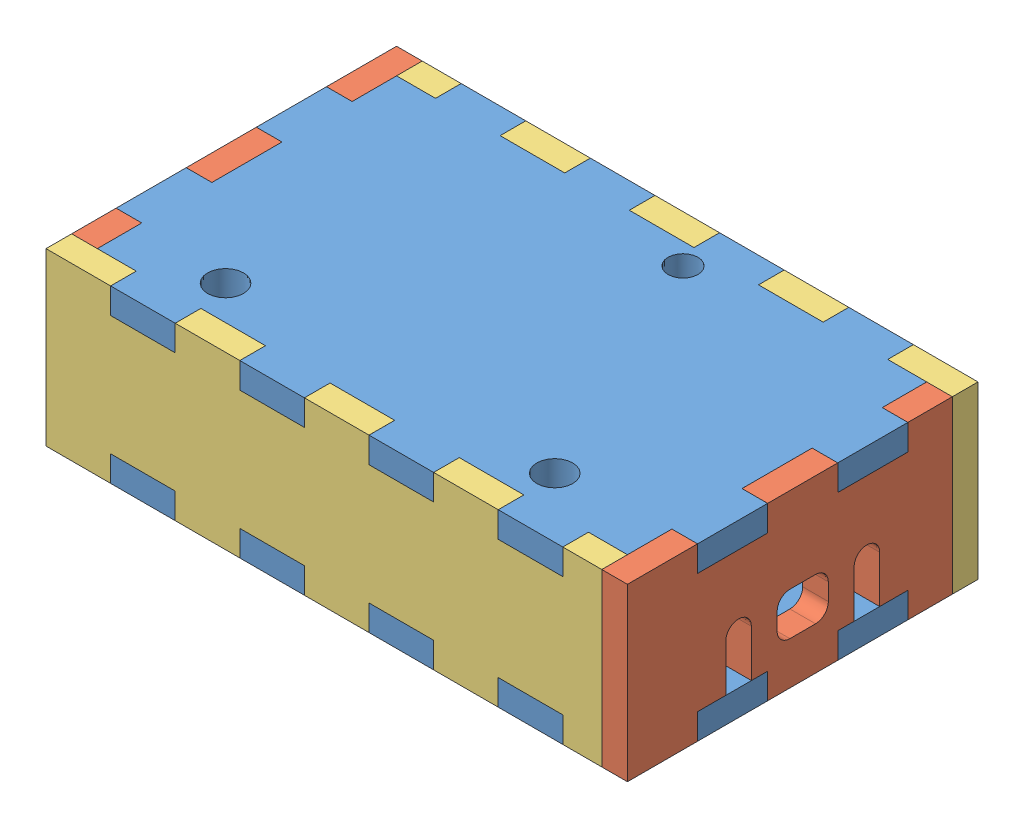
SolidWorks assembly DC-DC Buck LED, configuration Default. Lengths in mm.
Overall size (68 20 41).
6 component instances, 3 part files, 18 mates.
Components (placement in the parent):
- unten_oben-1: unten_oben [unten] at (-9.1679 54.5344 97.0759) size (68 3 41)
- rechts_links-1: rechts_links [rechts] at (58.833 74.5344 97.0759) x (0 0 -1) z (0 1 0) size (38 3 20)
- vorne_hinten-1: vorne_hinten [vorne] at (-9.1679 74.5344 97.0759) x (1 0 0) z (0 1 0) size (65 3 20)
- unten_oben-3: unten_oben [oben] at (-9.1679 71.5344 97.0759) size (68 3 41)
- rechts_links-4: rechts_links [links] at (-9.1679 74.5344 56.0765) x (0 0 1) z (0 1 0) size (38 3 20)
- vorne_hinten-4: vorne_hinten [hinten] at (58.833 74.5344 56.0765) x (-1 0 0) z (0 1 0) size (65 3 20)
Mates (geometry in assembly coordinates):
- Deckungsgleich12: coincident aligned: plane of unten_oben-1 through (-9.1679 54.5344 97.0759) normal (0 -1 0); plane of rechts_links-1 through (55.833 54.5344 80.6757) normal (0 -1 0)
- Deckungsgleich14: coincident aligned: plane of unten_oben-1 through (-9.1679 57.5344 89.4649) normal (-1 0 0); plane of ? through (-9.1679 123.5344 97.0097) normal (-1 0 0)
- Deckungsgleich17: coincident aligned: plane of unten_oben-1 through (-9.1679 54.5344 97.0759) normal (0 -1 0); plane of ? through (-9.1679 54.5344 51.737) normal (0 -1 0)
- Deckungsgleich19: coincident aligned: plane of unten_oben-1 through (-0.7135 57.5344 97.0097) normal (0 0 1); plane of ? through (-9.1679 62.2019 97.0097) normal (0 0 1)
- Deckungsgleich22: coincident aligned: plane of unten_oben-1 through (-9.1679 54.5344 97.0759) normal (0 -1 0); plane of vorne_hinten-1 through (21.054 54.5344 94.0759) normal (0 -1 0)
- Deckungsgleich32: coincident aligned: plane of rechts_links-4 through (-9.1679 74.5344 56.0765) normal (-1 0 0); plane of unten_oben-3 through (-9.1679 74.5344 80.6762) normal (-1 0 0)
- Deckungsgleich38: coincident aligned: plane of unten_oben-3 through (-1.6122 74.5344 56.0765) normal (0 0 -1); plane of rechts_links-4 through (-6.1679 74.5344 56.0765) normal (0 0 -1)
- Deckungsgleich39: coincident aligned: plane of unten_oben-3 through (-9.1679 74.5344 97.0759) normal (0 1 0); plane of rechts_links-4 through (-6.1679 74.5344 56.0765) normal (0 1 0)
- Deckungsgleich43: coincident aligned: plane of unten_oben-1 through (13.4996 57.5344 97.0759) normal (0 0 1); plane of vorne_hinten-1 through (-9.1679 74.5344 97.0759) normal (0 0 1)
- Deckungsgleich45: coincident aligned: plane of vorne_hinten-1 through (-9.1679 74.5344 97.0759) normal (0 0 1); plane of unten_oben-3 through (43.7212 74.5344 97.0759) normal (0 0 1)
- Deckungsgleich46: coincident aligned: plane of unten_oben-1 through (-9.1679 57.5344 80.6762) normal (-1 0 0); plane of rechts_links-4 through (-9.1679 74.5344 56.0765) normal (-1 0 0)
- Deckungsgleich47: coincident aligned: plane of unten_oben-1 through (-9.1679 54.5344 97.0759) normal (0 -1 0); plane of rechts_links-4 through (-6.1679 54.5344 88.8768) normal (0 -1 0)
- Deckungsgleich48: coincident aligned: plane of unten_oben-1 through (-1.6122 57.5344 56.0765) normal (0 0 -1); plane of vorne_hinten-4 through (58.833 74.5344 56.0765) normal (0 0 -1)
- Deckungsgleich49: coincident aligned: plane of unten_oben-1 through (-9.1679 54.5344 97.0759) normal (0 -1 0); plane of vorne_hinten-4 through (-1.6117 54.5344 59.0765) normal (0 -1 0)
- Deckungsgleich50: coincident anti-aligned: plane of rechts_links-4 through (-6.1679 74.5344 56.0765) normal (1 0 0); plane of vorne_hinten-4 through (-6.1679 74.5344 59.0765) normal (-1 0 0)
- Deckungsgleich51: coincident aligned: plane of unten_oben-1 through (58.833 57.5344 64.2759) normal (1 0 0); plane of rechts_links-1 through (58.833 74.5344 97.0759) normal (1 0 0)
- Deckungsgleich52: coincident anti-aligned: plane of rechts_links-1 through (55.833 74.5344 59.0765) normal (0 0 -1); plane of vorne_hinten-4 through (58.833 74.5344 59.0765) normal (0 0 1)
- Deckungsgleich53: coincident anti-aligned: plane of rechts_links-1 through (55.833 74.5344 97.0759) normal (-1 0 0); plane of vorne_hinten-1 through (55.833 74.5344 94.0759) normal (1 0 0)
